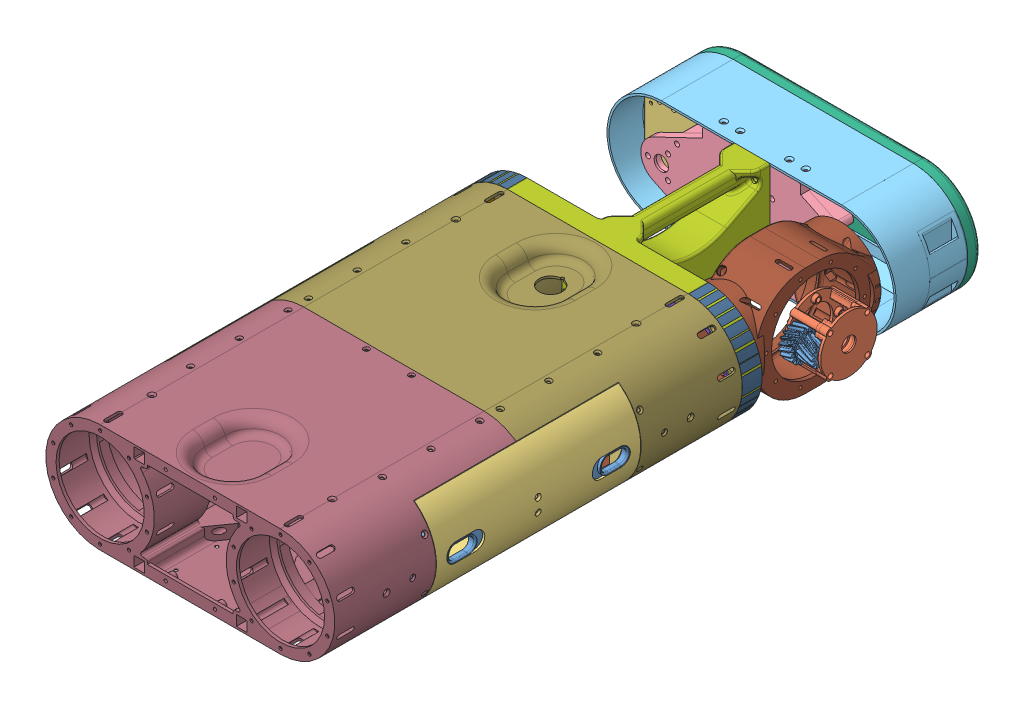
SolidWorks assembly DogBot V4, configuration Default. Lengths in mm.
Overall size (305.11 109.08 630.5).
36 component instances, 24 part files, 0 mates.
Components (placement in the parent):
- DogBot V4.stp-1: DogBot V4.stp [Default] at origin size (305.11 109.08 630.5)
  - HipAndLeg.stp-1: HipAndLeg.stp [Default] at origin size (297.25 109.08 232.9)
    - LegDrive.stp-1: LegDrive.stp [Default] at origin size (35.5 55 65.06)
      - PlanetGear.stp-1: PlanetGear.stp [Default] at origin size (28 30.03 30.11)
      - Carrier.stp-1: Carrier.stp [Default] at origin size (35.5 55 55)
    - Hip.stp-1: Hip.stp [Default] at origin size (282 109.08 232.9)
      - Pelvis.stp-1: Pelvis.stp [Default] at origin size (282 109.04 232.9)
        - PelvisB2.stp-1: PelvisB2.stp [Default] at origin size (235 102 48.05)
          - MotorDriverCase.stp-1: MotorDriverCase.stp [Default] at (-370.75 0 -50.05) x (0 0 1) z (0 -1 0) size (26.05 137.7 72)
          - PelvisB2-0.stp-1: PelvisB2-0.stp [Default] at origin size (216 102 22)
        - PelivsBumper.stp-1: PelivsBumper.stp [Default] at origin size (282 106 83)
          - BackCover.stp-1: BackCover.stp [Default] at origin size (282 106 70)
          - FrontCover.stp-1: FrontCover.stp [Default] at origin size (282 106 13)
        - Pelvis-1.stp-1: Pelvis-1.stp [Default] at origin size (282 109.04 149.9)
        - Pelvis-2.stp-1: Pelvis-2.stp [Default] at origin size (91 91 18.45)
        - Pelvis-3.stp-1: Pelvis-3.stp [Default] at origin size (91 91 18.45)
      - HipFixedGear.stp-1: HipFixedGear.stp [Default] at origin size (282 106 19.25)
      - HipDrive.stp-1: HipDrive.stp [Default] at origin size (80.99 106.04 135.18)
  - Torso.stp-1: Torso.stp [Default] at origin size (297.71 106.07 397.6)
    - Shell.stp-1: Shell.stp [Default] at origin size (282.02 106.07 397.6)
      - ShellB.stp-1: ShellB.stp [Default] at origin size (282.02 106.05 208.8)
      - ShellA.stp-1: ShellA.stp [Default] at origin size (282.02 106.07 208.8)
    - BatteryCompartment.stp-1: BatteryCompartment.stp [Default] at origin size (297.71 102.98 224)
      - BatteryCover.stp-1: BatteryCover.stp [Default] at origin size (60.76 85.4 209.4)
        - Slider.stp-1: Slider.stp [Default] at origin size (11.95 25.67 209.4)
        - Turnigy HardCase 5.0 Holder.stp-1: Turnigy HardCase 5.0 Holder.stp [Default] at origin size (20 78.8 36.95)
        - BatteryCover-4.stp-1: BatteryCover-4.stp [Default] at origin size (60.76 85.4 199.4)
        - BatteryCover-5.stp-1: BatteryCover-5.stp [Default] at origin size (7.25 47.18 195.4)
        - BatteryCover-6.stp-1: BatteryCover-6.stp [Default] at origin size (49.09 79.2 12)
      - BatteryCover(Mirror).stp-1: BatteryCover(Mirror).stp [Default] at (-373.5 0 0) x (-1 0 0) z (0 0 -1) size (60.76 85.4 209.4)
        - Slider(Mirror).stp-1: Slider(Mirror).stp [Default] at origin size (11.95 25.67 209.4)
        - Turnigy HardCase 5.0 Holder(Mirror).stp-1: Turnigy HardCase 5.0 Holder(Mirror).stp [Default] at origin size (20 78.8 36.95)
        - BatteryCover(Mirror)-7.stp-1: BatteryCover(Mirror)-7.stp [Default] at origin size (60.76 85.4 199.4)
        - BatteryCover(Mirror)-8.stp-1: BatteryCover(Mirror)-8.stp [Default] at origin size (6.2 47.18 195.4)
        - BatteryCover(Mirror)-9.stp-1: BatteryCover(Mirror)-9.stp [Default] at origin size (49.09 79.2 12)
      - BatteryCompartment-10.stp-1: BatteryCompartment-10.stp [Default] at origin size (51.42 102.98 224)
